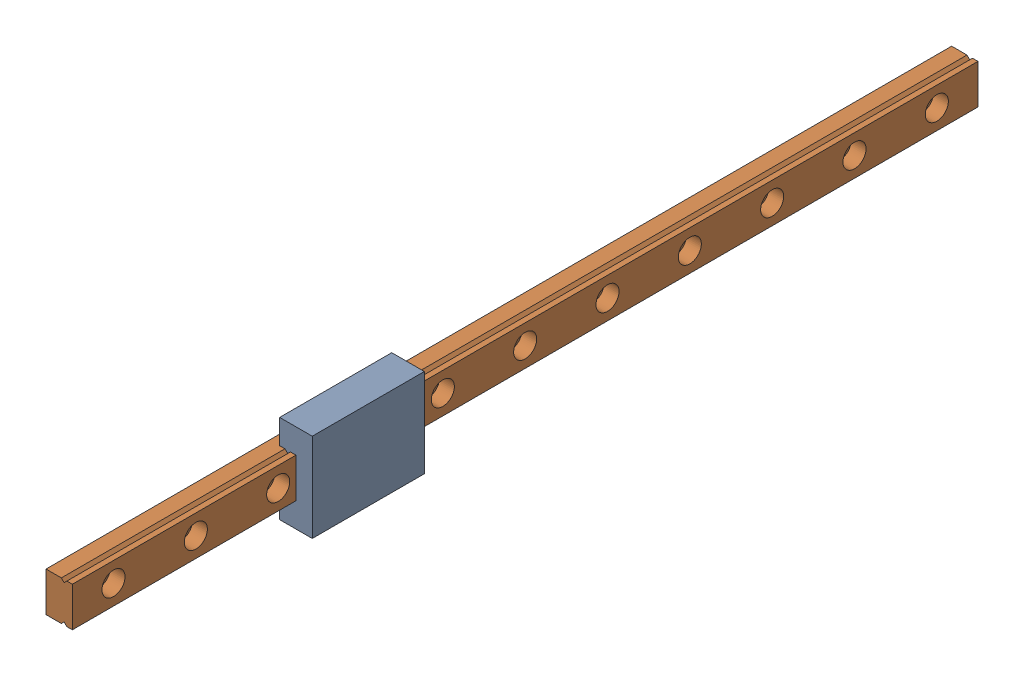
SolidWorks assembly Mandelbot_3_5_0_X_LinearRail_and_Slider_assembly_LDC+SMB_20171022_1611, configuration Default. Lengths in mm.
Overall size (12.95 26.9 275).
2 component instances, 2 part files, 2 mates.
Components (placement in the parent):
- Mandelbot_3_5_0_Xz_Gantry_assembly_X_Linear_Slider_carriage_part-v1_LDC+SMB_201710222_1616-1: Mandelbot_3_5_0_Xz_Gantry_assembly_X_Linear_Slider_carriage_part-v1_LDC+SMB_201710222_1616 [Default] at (-51.6536 -526.2644 -241.0037) x (0 -1 0) z (0 0 1) size (26.9 9.9 34.04)
- Mandelbot_3_5_0_Xz_Gantry_assembly_X_Linear_Slider_rail_part-v1_LDC+SMB_201710222_1616-1: Mandelbot_3_5_0_Xz_Gantry_assembly_X_Linear_Slider_rail_part-v1_LDC+SMB_201710222_1616 [Default] at (-51.6536 -526.2644 -414.0696) x (0 -1 0) z (0 0 1) size (12 8 275)
Mates (geometry in assembly coordinates):
- Coincident111: coincident: line of assembly; line of assembly; line of Mandelbot_3_5_0_Xz_Gantry_assembly_X_Linear_Slider_rail_part-v1_LDC+SMB_201710222_1616-1 through (-49.1536 -521.0977 -139.0696) axis (0 0 -1); line of Mandelbot_3_5_0_Xz_Gantry_assembly_X_Linear_Slider_carriage_part-v1_LDC+SMB_201710222_1616-1 through (-49.1536 -521.0977 -206.9677) axis (0 0 -1)
- Coincident112: coincident: line of assembly; line of assembly; line of Mandelbot_3_5_0_Xz_Gantry_assembly_X_Linear_Slider_rail_part-v1_LDC+SMB_201710222_1616-1 through (-49.1536 -531.431 -139.0696) axis (0 0 -1); line of Mandelbot_3_5_0_Xz_Gantry_assembly_X_Linear_Slider_carriage_part-v1_LDC+SMB_201710222_1616-1 through (-49.1536 -531.431 -206.9677) axis (0 0 -1)
